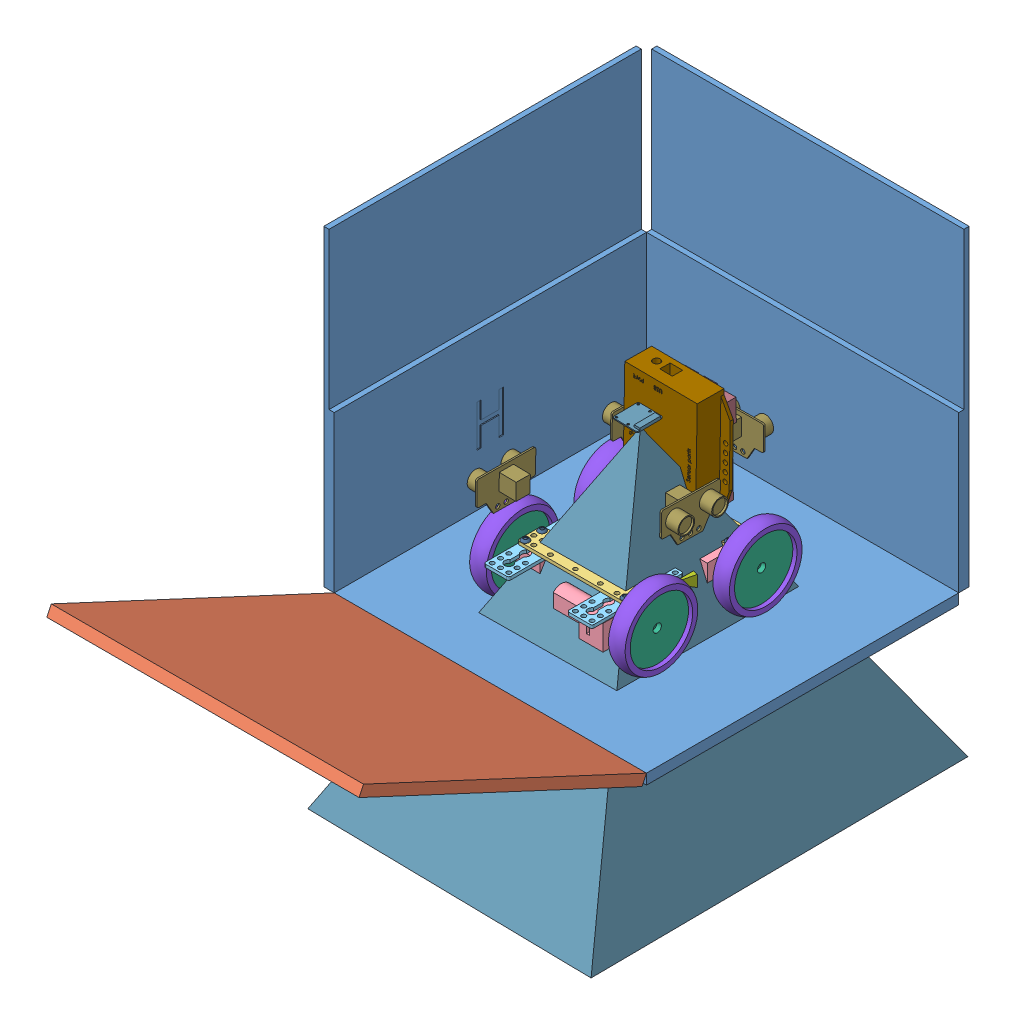
SolidWorks assembly robot_asm_standing, configuration Default. Lengths in mm.
Overall size (310 458.47 599.43).
43 component instances, 14 part files, 79 mates.
Components (placement in the parent):
- maze-2: maze [Default] at origin size (310 310 586.12)
  - maze_cell-1: maze_cell [Default] at origin size (310 310 310)
  - maze_slope-1: maze_slope [Default] at (0 -9.0631 4.2262) x (0 0.422618 0.906308) z (-1 0 0) size (300 10 300)
- T-bracket-1: T-bracket [Default] at (151.056 49 -176.8271) size (104 3 84)
- T-bracket-2: T-bracket [Default] at (151.056 52 -100.6271) x (-1 0 0) z (0 0 -1) size (104 3 84)
- encoder_motor-1: encoder_motor [Default] at (98.606 37 -222.7771) x (1 0 0) z (0 -1 0) size (64 46.4 24)
- encoder_motor-2: encoder_motor [Default] at (203.506 37 -154.8771) x (-1 0 0) z (0 -1 0) size (64 46.4 24)
- bracket-1: bracket [Default] at (99.056 49 -44.6271) size (24 3 88)
- bracket-3: bracket [Default] at (179.056 49 -44.6271) size (24 3 88)
- encoder_motor-5: encoder_motor [Default] at (98.606 37 -122.5771) x (1 0 0) z (0 -1 0) size (64 46.4 24)
- encoder_motor-7: encoder_motor [Default] at (203.506 37 -54.6771) x (-1 0 0) z (0 -1 0) size (64 46.4 24)
- wheels-1: wheels [Default] at (88.606 37 -88.3771) x (0 0 1) z (-1 0 0) size (65.99 65.99 16)
- wheels-2: wheels [Default] at (88.606 37 -188.5771) x (0 0 -1) z (-1 0 0) size (65.99 65.99 16)
- wheels-4: wheels [Default] at (213.506 37 -189.0771) x (0 0 1) z (1 0 0) size (65.99 65.99 16)
- wheels-6: wheels [Default] at (213.506 37 -88.8771) x (0 0 1) z (1 0 0) size (65.99 65.99 16)
- battery-1: battery [Default] at (101.0776 22.441 -170.1455) x (-0.233445 0 0.97237) z (-0.97237 0 -0.233445) size (35 21.7 105)
- tire-1: tire [Default] at (217.506 37 -88.8771) x (1 0 0) z (0 0.015768 -0.999876) size (16 74 74)
- tire-2: tire [Default] at (217.506 37 -189.0771) x (1 0 0) z (0 0.062402 -0.998051) size (16 74 74)
- tire-4: tire [Default] at (84.606 37 -188.5771) x (-1 0 0) z (0 -0.99927 0.038207) size (16 74 74)
- tire-6: tire [Default] at (84.606 37 -88.3771) x (-1 0 0) z (0 -0.815244 0.579117) size (16 74 74)
- auriga_board-1: auriga_board [Default] at (151.447 169.1988 -188.2966) x (-0.999962 0.008726 -0.000076) z (0.008727 0.999924 -0.008726) size (88.1 25.8 109.5)
- bigscrew-1: bigscrew [Default] at (103.056 42 -196.8271) x (0.999863 0 0.016576) z (-0.016576 0 0.999863) size (7.5 12 7.5)
- bigscrew-2: bigscrew [Default] at (103.056 42 -180.8271) x (0.985071 0 -0.17215) z (0.17215 0 0.985071) size (7.5 12 7.5)
- bigscrew-3: bigscrew [Default] at (199.056 42 -196.8271) x (0.924799 0 -0.380457) z (0.380457 0 0.924799) size (7.5 12 7.5)
- bigscrew-4: bigscrew [Default] at (199.056 42 -180.8271) x (0.809836 0 -0.586657) z (0.586657 0 0.809836) size (7.5 12 7.5)
- bigscrew-6: bigscrew [Default] at (159.056 45 -148.8271) x (0.646317 0 -0.763069) z (0.763069 0 0.646317) size (7.5 12 7.5)
- bigscrew-8: bigscrew [Default] at (143.056 45 -148.8271) x (0.458424 0 -0.888734) z (0.888734 0 0.458424) size (7.5 12 7.5)
- bigscrew-10: bigscrew [Default] at (159.056 45 -128.6271) x (0.282723 0 -0.959201) z (0.959201 0 0.282723) size (7.5 12 7.5)
- bigscrew-11: bigscrew [Default] at (143.056 45 -128.6271) x (0.069298 0 -0.997596) z (0.997596 0 0.069298) size (7.5 12 7.5)
- bigscrew-12: bigscrew [Default] at (199.056 45 -80.6271) x (-0.166501 0 -0.986041) z (0.986041 0 -0.166501) size (7.5 12 7.5)
- bigscrew-13: bigscrew [Default] at (199.056 45 -96.6271) x (-0.397145 0 -0.917756) z (0.917756 0 -0.397145) size (7.5 12 7.5)
- bigscrew-14: bigscrew [Default] at (103.056 45 -80.6271) x (-0.593123 0 -0.805112) z (0.805112 0 -0.593123) size (7.5 12 7.5)
- bigscrew-15: bigscrew [Default] at (103.056 45 -96.6271) x (-0.736724 0 -0.676194) z (0.676194 0 -0.736724) size (7.5 12 7.5)
- nut-1: nut [Default] at (159.056 47.5 -128.6271) x (0.999863 0 0.016576) z (-0.016576 0 0.999863) size (8.21 3.51 7.16)
- nut-2: nut [Default] at (143.056 47.5 -128.6271) x (0.985071 0 -0.17215) z (0.17215 0 0.985071) size (8.21 3.51 7.16)
- nut-3: nut [Default] at (143.056 47.5 -148.8271) x (0.924799 0 -0.380457) z (0.380457 0 0.924799) size (8.21 3.51 7.16)
- nut-4: nut [Default] at (159.056 47.5 -148.8271) x (0.809836 0 -0.586657) z (0.586657 0 0.809836) size (8.21 3.51 7.16)
- ultrasonic_sensor-1: ultrasonic_sensor [Default] at (203.7056 79.8585 -136.9759) x (0.00865 -0.008726 -0.999925) z (-0.008802 -0.999924 0.00865) size (56 29.8 36)
- ultrasonic_sensor-2: ultrasonic_sensor [Default] at (98.2358 77.7933 -196.3636) x (-0.008727 0.017452 0.99981) z (-0.008726 -0.999811 0.017376) size (56 29.8 36)
- ultrasonic_sensor-3: ultrasonic_sensor [Default] at (153.5155 78.7527 -231.0719) x (-0.999962 -0.008726 0.000076) z (0.008727 -0.999924 0.008726) size (56 29.8 36)
- ultrasonic_sensor-4: ultrasonic_sensor [Default] at (88.0615 77.4904 -77.0512) x (-0.008727 0 0.999962) z (-0.008726 -0.999962 -0.000076) size (56 29.8 36)
- raspberrypi_4-1: raspberrypi_4 [Default] at (128.6478 62.9247 -190.0785) x (-0.008727 0.999924 0.008725) z (-0.999962 -0.008726 -0.000152) size (88 17.5 57.5)
- picamera-1: picamera [Default] at (163.921 152.3737 -152.1545) x (-0.000076 -0.008726 0.999962) z (0.999848 -0.017452 -0.000076) size (361.94 309 272.17)
Mates (geometry in assembly coordinates):
- Concentric1: concentric aligned: cylinder of T-bracket-1 through (143.056 49 -148.8271) axis (0 1 0) radius 2.1; cylinder of T-bracket-2 through (143.056 52 -148.8271) axis (0 1 0) radius 2.1
- Concentric2: concentric aligned: cylinder of T-bracket-1 through (159.056 49 -128.6271) axis (0 1 0) radius 2.1; cylinder of T-bracket-2 through (159.056 52 -128.6271) axis (0 1 0) radius 2.1
- Coincident1: coincident anti-aligned: plane of T-bracket-1 through (151.056 52 -176.8271) normal (0 1 0); plane of T-bracket-2 through (151.056 52 -100.6271) normal (0 -1 0)
- Concentric5: concentric aligned: cylinder of T-bracket-1 through (103.056 49 -196.8271) axis (0 1 0) radius 2.1; cylinder of encoder_motor-1 through (103.056 43.5 -196.8271) axis (0 1 0) radius 1.95
- Concentric6: concentric aligned: cylinder of T-bracket-1 through (103.056 49 -180.8271) axis (0 1 0) radius 2.1; cylinder of encoder_motor-1 through (103.056 43.5 -180.8271) axis (0 1 0) radius 1.95
- Coincident3: coincident anti-aligned: plane of T-bracket-1 through (151.056 49 -176.8271) normal (0 -1 0); plane of encoder_motor-1 through (98.606 49 -222.7771) normal (0 1 0)
- Concentric7: concentric aligned: cylinder of T-bracket-1 through (199.056 49 -180.8271) axis (0 1 0) radius 2.1; cylinder of encoder_motor-2 through (199.056 43.5 -180.8271) axis (0 1 0) radius 1.95
- Concentric8: concentric aligned: cylinder of T-bracket-1 through (199.056 49 -196.8271) axis (0 1 0) radius 2.1; cylinder of encoder_motor-2 through (199.056 43.5 -196.8271) axis (0 1 0) radius 1.95
- Coincident4: coincident anti-aligned: plane of T-bracket-1 through (151.056 49 -176.8271) normal (0 -1 0); plane of encoder_motor-2 through (203.506 49 -154.8771) normal (0 1 0)
- Concentric11: concentric aligned: cylinder of T-bracket-2 through (103.056 52 -96.6271) axis (0 1 0) radius 2.1; cylinder of bracket-1 through (103.056 49 -96.6271) axis (0 1 0) radius 2.1
- Concentric12: concentric aligned: cylinder of T-bracket-2 through (103.056 52 -80.6271) axis (0 1 0) radius 2.1; cylinder of bracket-1 through (103.056 49 -80.6271) axis (0 1 0) radius 2.1
- Coincident6: coincident anti-aligned: plane of T-bracket-2 through (151.056 52 -100.6271) normal (0 -1 0); plane of bracket-1 through (99.056 52 -44.6271) normal (0 1 0)
- Concentric13: concentric aligned: cylinder of T-bracket-2 through (199.056 52 -96.6271) axis (0 1 0) radius 2.1; cylinder of bracket-3 through (199.056 49 -96.6271) axis (0 1 0) radius 2.1
- Concentric14: concentric aligned: cylinder of T-bracket-2 through (199.056 52 -80.6271) axis (0 1 0) radius 2.1; cylinder of bracket-3 through (199.056 49 -80.6271) axis (0 1 0) radius 2.1
- Coincident7: coincident anti-aligned: plane of T-bracket-2 through (151.056 52 -100.6271) normal (0 -1 0); plane of bracket-3 through (179.056 52 -44.6271) normal (0 1 0)
- Concentric15: concentric aligned: cylinder of T-bracket-2 through (103.056 52 -96.6271) axis (0 1 0) radius 2.1; cylinder of encoder_motor-5 through (103.056 43.5 -96.6271) axis (0 1 0) radius 1.95
- Concentric16: concentric aligned: cylinder of T-bracket-2 through (103.056 52 -80.6271) axis (0 1 0) radius 2.1; cylinder of encoder_motor-5 through (103.056 43.5 -80.6271) axis (0 1 0) radius 1.95
- Coincident8: coincident anti-aligned: plane of bracket-1 through (99.056 49 -44.6271) normal (0 -1 0); plane of encoder_motor-5 through (98.606 49 -122.5771) normal (0 1 0)
- Concentric17: concentric aligned: cylinder of T-bracket-2 through (199.056 52 -80.6271) axis (0 1 0) radius 2.1; cylinder of encoder_motor-7 through (199.056 43.5 -80.6271) axis (0 1 0) radius 1.95
- Concentric18: concentric aligned: cylinder of T-bracket-2 through (199.056 52 -96.6271) axis (0 1 0) radius 2.1; cylinder of encoder_motor-7 through (199.056 43.5 -96.6271) axis (0 1 0) radius 1.95
- Coincident9: coincident anti-aligned: plane of bracket-3 through (179.056 49 -44.6271) normal (0 -1 0); plane of encoder_motor-7 through (203.506 49 -54.6771) normal (0 1 0)
- Concentric19: concentric aligned: cylinder of encoder_motor-5 through (89.606 37 -88.3771) axis (1 0 0) radius 2.7; cylinder of wheels-1 through (82.4773 37 -88.3771) axis (1 0 0) radius 2.75
- Parallel1: parallel anti-aligned: plane of encoder_motor-5 through (89.606 35.25 -76.1771) normal (0 -1 0); plane of wheels-1 through (82.4773 35.15 -86.3424) normal (0 1 0)
- Coincident11: coincident anti-aligned: plane of encoder_motor-5 through (96.606 35.25 -76.1771) normal (-1 0 0); plane of wheels-1 through (96.606 37 -88.3771) normal (1 0 0)
- Concentric20: concentric aligned: cylinder of encoder_motor-1 through (89.606 37 -188.5771) axis (1 0 0) radius 2.7; cylinder of wheels-2 through (82.4773 37 -188.5771) axis (1 0 0) radius 2.75
- Parallel2: parallel anti-aligned: plane of encoder_motor-1 through (89.606 38.75 -176.3771) normal (0 1 0); plane of wheels-2 through (82.4773 38.85 -190.6118) normal (0 -1 0)
- Coincident12: coincident anti-aligned: plane of encoder_motor-1 through (96.606 38.75 -176.3771) normal (-1 0 0); plane of wheels-2 through (96.606 37 -188.5771) normal (1 0 0)
- Concentric21: concentric aligned: cylinder of encoder_motor-2 through (212.506 37 -189.0771) axis (-1 0 0) radius 2.7; cylinder of wheels-4 through (219.6347 37 -189.0771) axis (-1 0 0) radius 2.75
- Parallel3: parallel anti-aligned: plane of encoder_motor-2 through (212.506 38.75 -201.2771) normal (0 1 0); plane of wheels-4 through (219.6347 38.85 -187.0424) normal (0 -1 0)
- Coincident13: coincident anti-aligned: plane of encoder_motor-2 through (205.506 38.75 -201.2771) normal (1 0 0); plane of wheels-4 through (205.506 37 -189.0771) normal (-1 0 0)
- Concentric22: concentric aligned: cylinder of encoder_motor-7 through (212.506 37 -88.8771) axis (-1 0 0) radius 2.7; cylinder of wheels-6 through (219.6347 37 -88.8771) axis (-1 0 0) radius 2.75
- Parallel4: parallel anti-aligned: plane of encoder_motor-7 through (212.506 38.75 -101.0771) normal (0 1 0); plane of wheels-6 through (219.6347 38.85 -86.8424) normal (0 -1 0)
- Coincident14: coincident anti-aligned: plane of encoder_motor-7 through (205.506 38.75 -101.0771) normal (1 0 0); plane of wheels-6 through (205.506 37 -88.8771) normal (-1 0 0)
- Concentric23: concentric aligned: cylinder of wheels-6 through (221.506 37 -88.8771) axis (-1 0 0) radius 33; cylinder of tire-1 through (-472.9608 37 -88.8771) axis (-1 0 0) radius 33
- Coincident16: coincident anti-aligned: plane of wheels-6 through (213.506 37 -88.8771) normal (-1 0 0); plane of tire-1 through (213.506 4.0041 -89.3974) normal (1 0 0)
- Concentric24: concentric aligned: cylinder of wheels-4 through (221.506 37 -189.0771) axis (-1 0 0) radius 33; cylinder of tire-2 through (-472.9608 37 -189.0771) axis (-1 0 0) radius 33
- Coincident17: coincident anti-aligned: plane of wheels-4 through (213.506 37 -189.0771) normal (-1 0 0); plane of tire-2 through (213.506 4.0643 -191.1363) normal (1 0 0)
- Concentric25: concentric aligned: cylinder of wheels-2 through (80.606 37 -188.5771) axis (1 0 0) radius 33; cylinder of tire-4 through (775.0728 37 -188.5771) axis (1 0 0) radius 33
- Coincident18: coincident anti-aligned: plane of wheels-2 through (88.606 37 -188.5771) normal (1 0 0); plane of tire-4 through (88.606 35.7392 -221.553) normal (-1 0 0)
- Concentric26: concentric aligned: cylinder of wheels-1 through (80.606 37 -88.3771) axis (1 0 0) radius 33; cylinder of tire-6 through (775.0728 37 -88.3771) axis (1 0 0) radius 33
- Coincident19: coincident anti-aligned: plane of wheels-1 through (88.606 37 -88.3771) normal (1 0 0); plane of tire-6 through (88.606 17.8891 -115.2802) normal (-1 0 0)
- Concentric27: concentric anti-aligned: cylinder of T-bracket-1 through (103.056 49 -196.8271) axis (0 1 0) radius 2.1; cylinder of bigscrew-1 through (103.056 -268.2059 -196.8271) axis (0 -1 0) radius 2
- Coincident20: coincident anti-aligned: plane of T-bracket-1 through (151.056 52 -176.8271) normal (0 1 0); plane of bigscrew-1 through (105.0557 52 -196.7939) normal (0 -1 0)
- Coincident21: coincident anti-aligned: plane of T-bracket-1 through (151.056 52 -176.8271) normal (0 1 0); plane of bigscrew-2 through (105.0261 52 -181.1714) normal (0 -1 0)
- Concentric28: concentric anti-aligned: cylinder of T-bracket-1 through (103.056 49 -180.8271) axis (0 1 0) radius 2.1; cylinder of bigscrew-2 through (103.056 -268.2059 -180.8271) axis (0 -1 0) radius 2
- Coincident22: coincident anti-aligned: plane of T-bracket-1 through (151.056 52 -176.8271) normal (0 1 0); plane of bigscrew-3 through (200.9056 52 -197.588) normal (0 -1 0)
- Concentric29: concentric anti-aligned: cylinder of T-bracket-1 through (199.056 49 -196.8271) axis (0 1 0) radius 2.1; cylinder of bigscrew-3 through (199.056 -268.2059 -196.8271) axis (0 -1 0) radius 2
- Coincident23: coincident anti-aligned: plane of T-bracket-1 through (151.056 52 -176.8271) normal (0 1 0); plane of bigscrew-4 through (200.6757 52 -182.0004) normal (0 -1 0)
- Concentric30: concentric anti-aligned: cylinder of T-bracket-1 through (199.056 49 -180.8271) axis (0 1 0) radius 2.1; cylinder of bigscrew-4 through (199.056 -268.2059 -180.8271) axis (0 -1 0) radius 2
- Coincident25: coincident anti-aligned: plane of T-bracket-2 through (151.056 55 -100.6271) normal (0 1 0); plane of bigscrew-6 through (160.3486 55 -150.3532) normal (0 -1 0)
- Concentric31: concentric anti-aligned: cylinder of T-bracket-2 through (159.056 52 -148.8271) axis (0 1 0) radius 2.1; cylinder of bigscrew-6 through (159.056 -265.2059 -148.8271) axis (0 -1 0) radius 2
- Concentric32: concentric anti-aligned: cylinder of T-bracket-2 through (143.056 52 -148.8271) axis (0 1 0) radius 2.1; cylinder of bigscrew-8 through (143.056 -265.2059 -148.8271) axis (0 -1 0) radius 2
- Coincident27: coincident anti-aligned: plane of T-bracket-2 through (151.056 55 -100.6271) normal (0 1 0); plane of bigscrew-8 through (143.9729 55 -150.6046) normal (0 -1 0)
- Coincident28: coincident anti-aligned: plane of T-bracket-2 through (151.056 55 -100.6271) normal (0 1 0); plane of bigscrew-10 through (159.6215 55 -130.5455) normal (0 -1 0)
- Concentric33: concentric anti-aligned: cylinder of T-bracket-2 through (159.056 52 -128.6271) axis (0 1 0) radius 2.1; cylinder of bigscrew-10 through (159.056 -265.2059 -128.6271) axis (0 -1 0) radius 2
- Coincident29: coincident anti-aligned: plane of T-bracket-2 through (151.056 55 -100.6271) normal (0 1 0); plane of bigscrew-11 through (143.1946 55 -130.6223) normal (0 -1 0)
- Concentric34: concentric anti-aligned: cylinder of T-bracket-2 through (143.056 52 -128.6271) axis (0 1 0) radius 2.1; cylinder of bigscrew-11 through (143.056 -265.2059 -128.6271) axis (0 -1 0) radius 2
- Coincident30: coincident anti-aligned: plane of T-bracket-2 through (151.056 55 -100.6271) normal (0 1 0); plane of bigscrew-12 through (198.723 55 -82.5992) normal (0 -1 0)
- Concentric35: concentric anti-aligned: cylinder of T-bracket-2 through (199.056 52 -80.6271) axis (0 1 0) radius 2.1; cylinder of bigscrew-12 through (199.056 -265.2059 -80.6271) axis (0 -1 0) radius 2
- Coincident31: coincident anti-aligned: plane of T-bracket-2 through (151.056 55 -100.6271) normal (0 1 0); plane of bigscrew-13 through (198.2617 55 -98.4626) normal (0 -1 0)
- Concentric36: concentric anti-aligned: cylinder of T-bracket-2 through (199.056 52 -96.6271) axis (0 1 0) radius 2.1; cylinder of bigscrew-13 through (199.056 -265.2059 -96.6271) axis (0 -1 0) radius 2
- Coincident32: coincident anti-aligned: plane of T-bracket-2 through (151.056 55 -100.6271) normal (0 1 0); plane of bigscrew-14 through (101.8698 55 -82.2373) normal (0 -1 0)
- Concentric37: concentric anti-aligned: cylinder of T-bracket-2 through (103.056 52 -80.6271) axis (0 1 0) radius 2.1; cylinder of bigscrew-14 through (103.056 -265.2059 -80.6271) axis (0 -1 0) radius 2
- Coincident33: coincident anti-aligned: plane of T-bracket-2 through (151.056 55 -100.6271) normal (0 1 0); plane of bigscrew-15 through (101.5826 55 -97.9795) normal (0 -1 0)
- Concentric38: concentric anti-aligned: cylinder of T-bracket-2 through (103.056 52 -96.6271) axis (0 1 0) radius 2.1; cylinder of bigscrew-15 through (103.056 -265.2059 -96.6271) axis (0 -1 0) radius 2
- Concentric39: concentric aligned: cylinder of bigscrew-10 through (159.056 -265.2059 -128.6271) axis (0 -1 0) radius 2; cylinder of nut-1 through (159.056 49 -128.6271) axis (0 -1 0) radius 2
- Coincident35: coincident anti-aligned: plane of T-bracket-1 through (151.056 49 -176.8271) normal (0 -1 0); plane of nut-1 through (159.056 49 -128.6271) normal (0 1 0)
- Coincident36: coincident anti-aligned: plane of T-bracket-1 through (151.056 49 -176.8271) normal (0 -1 0); plane of nut-2 through (143.056 49 -128.6271) normal (0 1 0)
- Concentric40: concentric aligned: cylinder of bigscrew-11 through (143.056 -265.2059 -128.6271) axis (0 -1 0) radius 2; cylinder of nut-2 through (143.056 49 -128.6271) axis (0 -1 0) radius 2
- Coincident37: coincident anti-aligned: plane of T-bracket-1 through (151.056 49 -176.8271) normal (0 -1 0); plane of nut-3 through (143.056 49 -148.8271) normal (0 1 0)
- Concentric41: concentric aligned: cylinder of bigscrew-8 through (143.056 -265.2059 -148.8271) axis (0 -1 0) radius 2; cylinder of nut-3 through (143.056 49 -148.8271) axis (0 -1 0) radius 2
- Coincident38: coincident anti-aligned: plane of T-bracket-1 through (151.056 49 -176.8271) normal (0 -1 0); plane of nut-4 through (159.056 49 -148.8271) normal (0 1 0)
- Concentric42: concentric aligned: cylinder of bigscrew-6 through (159.056 -265.2059 -148.8271) axis (0 -1 0) radius 2; cylinder of nut-4 through (159.056 49 -148.8271) axis (0 -1 0) radius 2
- Tangent1: tangent anti-aligned: torus of tire-4; plane of maze-2/maze_cell-1 through (0 0 0) normal (0 1 0)
- Tangent4: tangent anti-aligned: plane of maze-2/maze_slope-1 through (0 0 0) normal (0 0.906308 0.422618); torus of tire-1
- Tangent6: tangent anti-aligned: plane of maze-2/maze_cell-1 through (0 0 0) normal (0 1 0); torus of tire-2
- Tangent7: tangent anti-aligned: plane of maze-2/maze_slope-1 through (0 0 0) normal (0 0.906308 0.422618); torus of tire-6
- Tangent8: tangent anti-aligned: plane of maze-2/maze_cell-1 through (0 0 0) normal (0 1 0); torus of tire-1
- Parallel7: parallel aligned: plane of maze-2/maze_cell-1 through (300 -10 0) normal (1 0 0); plane of wheels-6 through (221.506 37 -88.8771) normal (1 0 0)
